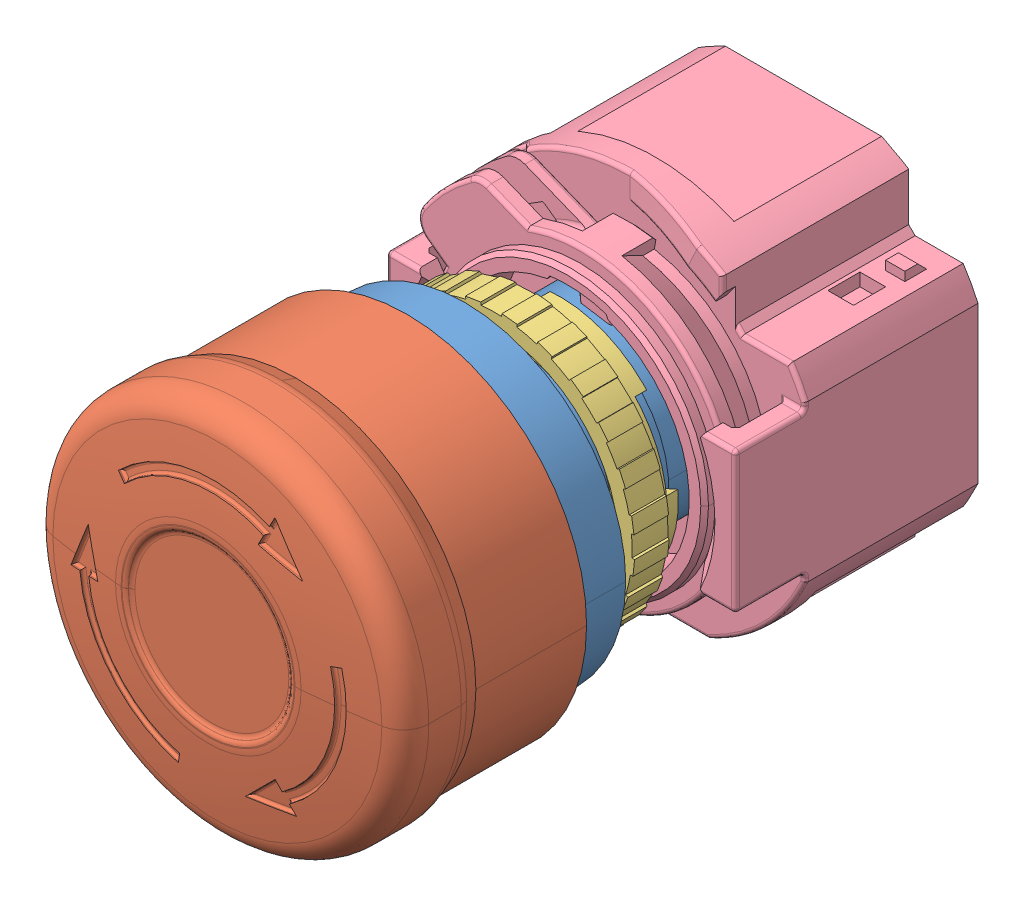
SolidWorks assembly cad_STEP_OUTSIDE-XA1E-BV3__R, configuration 預設. Lengths in mm.
Overall size (29 29.42 48.5).
5 component instances, 4 part files, 0 mates.
Components (placement in the parent):
- cad_STEP_OUTSIDE-XA1E-BV3__R.STEP-1: cad_STEP_OUTSIDE-XA1E-BV3__R.STEP [預設] at origin size (29 29.42 48.5)
  - OUTSIDE-XA-BODY-V-Y.STEP-1: OUTSIDE-XA-BODY-V-Y.STEP [預設] at origin size (25.2 25.2 25.5)
  - OUTSIDE-XA-HANDLE-BV-__.STEP-1: OUTSIDE-XA-HANDLE-BV-__.STEP [預設] at (0 0 32.9) size (29 29 15.5)
  - OUTSIDE-XA-LOCK-NUT.STEP-1: OUTSIDE-XA-LOCK-NUT.STEP [預設] at (0 0 10.55) x (0.406188 -0.91379 0) z (0 0 1) size (21.8 21.8 5.1)
  - OUTSIDE-XA-C____-_______.STEP-1: OUTSIDE-XA-C____-_______.STEP [預設] at origin size (27.99 28.54 21.6)
